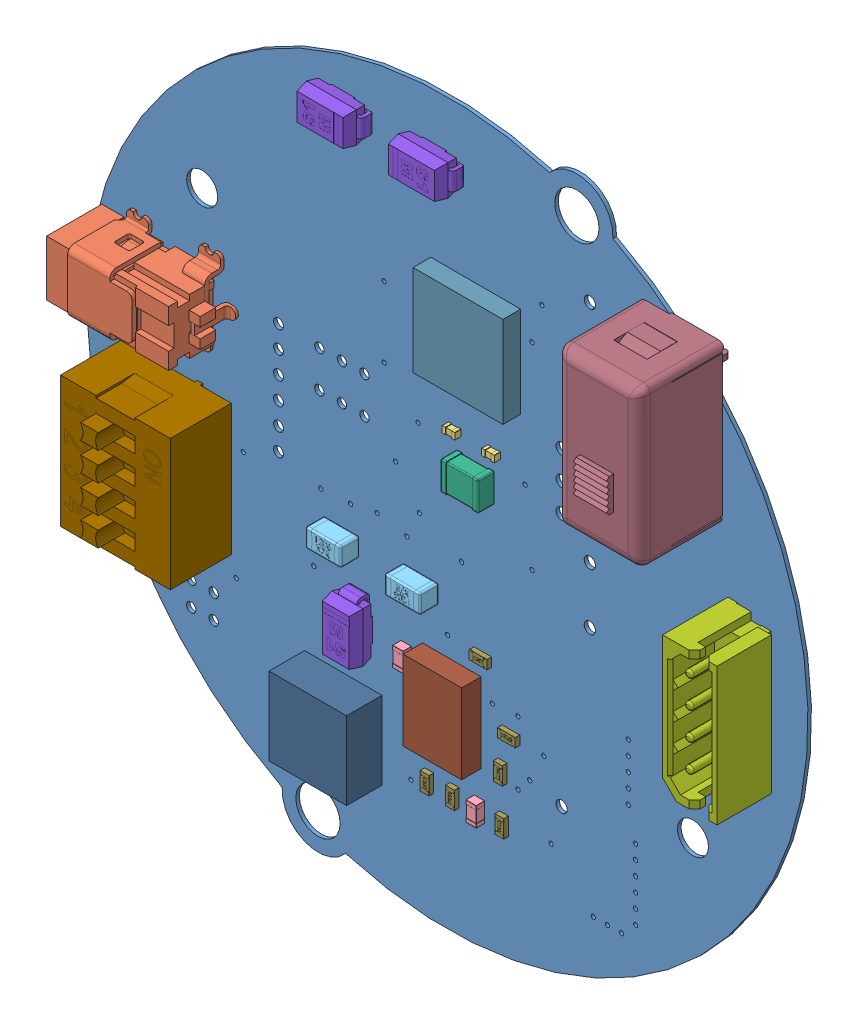
SolidWorks assembly sb, configuration Default. Lengths in mm.
Overall size (65 65 12.24).
40 component instances, 19 part files, 0 mates.
Components (placement in the parent):
- sb-1: sb [Default] at origin size (65 65 0.32)
- DRILL_4MM_DRILL_4MM-1: DRILL_4MM_DRILL_4MM [Default] at (11.6586 29.0576 0.3226) size (4.08 4.08 0)
- DRILL_4MM_DRILL_4MM-2: DRILL_4MM_DRILL_4MM [Default] at (-11.684 -29.083 0.3226) size (4.08 4.08 0)
- pj-032h-smt-tr-1: pj-032h-smt-tr [Default] at (-31.1624 6.0354 0.3105) x (0 -1 0) z (-1 0 0) size (8.2 6 12.3)
- 0402c_2320560-1: 0402c_2320560 [Default] at (0.635 6.858 0.3226) size (1.15 0.6 0.55)
- 0402c_2320560-2: 0402c_2320560 [Default] at (4.191 6.858 0.3226) x (-1 0 0) z (0 0 1) size (1.15 0.6 0.55)
- 0603C-1: 0603C [Default] at (2.794 -21.717 0.3226) x (0 -1 0) z (0 0 1) size (1.75 0.95 0.87)
- 0603C-2: 0603C [Default] at (-3.81 -12.954 0.3226) x (0 -1 0) z (0 0 1) size (1.75 0.95 0.87)
- Capacitor Vishay 1206 X7R-1: Capacitor Vishay 1206 X7R [По умолчанию] at (-9.525 -6.604 0.3226) size (3.2 1.7 1.7)
- Capacitor Vishay 1206 X7R-2: Capacitor Vishay 1206 X7R [По умолчанию] at (-2.3876 -6.7056 0.3226) x (-1 0 0) z (0 0 1) size (3.2 1.7 1.7)
- CAP1210-1: CAP1210 [Default] at (0.8315 4.0884 0.2929) x (1 0 0) z (0 -1 0) size (3.4 1.5 2.6)
- PORT-1: PORT [Default] at (27.7057 -0.1304 3.2566) x (0 1 0) z (1 0 0) size (12.4 9.4 4.9)
- DO-214AC-1: DO-214AC [Default] at (-9.398 27.051 1.3859) x (-1 0 0) z (0 0 1) size (5.28 2.79 2.29)
- DO-214AC-2: DO-214AC [Default] at (-1.143 27.051 1.3859) size (5.28 2.79 2.29)
- DO-214AC-3: DO-214AC [Default] at (-7.874 -12.3846 1.4768) x (0 -1 0) z (0 0 1) size (5.28 2.79 2.29)
- DS-4-1: DS-4 [Default] at (-29.1408 -0.9205 0.5763) x (0 -1 0) z (-1 0 0) size (11.82 10.4 9.9)
- HEADER_HEADER-1: HEADER_HEADER [Default] at (-21.082 -18.923 0.3226) size (2.12 2.13 0)
- HEADER_HEADER-2: HEADER_HEADER [Default] at (-21.082 -16.764 0.3226) size (2.12 2.13 0)
- HEADER_HEADER-3: HEADER_HEADER [Default] at (-23.114 -16.764 0.3226) size (2.12 2.13 0)
- HEADER_HEADER-4: HEADER_HEADER [Default] at (-23.114 -18.923 0.3226) size (2.12 2.13 0)
- HEADER_HEADER-5: HEADER_HEADER [Default] at (-11.557 3.81 0.3226) size (2.12 2.13 0)
- HEADER_HEADER-6: HEADER_HEADER [Default] at (-9.525 3.81 0.3226) size (2.12 2.13 0)
- HEADER_HEADER-7: HEADER_HEADER [Default] at (-7.493 3.81 0.3226) size (2.12 2.13 0)
- HEADER_HEADER-8: HEADER_HEADER [Default] at (-11.557 7.112 0.3226) size (2.12 2.13 0)
- HEADER_HEADER-9: HEADER_HEADER [Default] at (-9.525 7.112 0.3226) size (2.12 2.13 0)
- HEADER_HEADER-10: HEADER_HEADER [Default] at (-7.493 7.112 0.3226) size (2.12 2.13 0)
- inductor7mm-1: inductor7mm [Default] at (-5.907 -17.187 0.3226) x (-1 0 0) z (0 0 1) size (6.99 7.01 3.2)
- SOIC8_MP1584_BUCK_MP1584_BUCK-1: SOIC8_MP1584_BUCK_MP1584_BUCK [Default] at (0.381 -14.859 0.3226) x (0 1 0) z (0 0 1) size (7.18 5.28 1.75)
- ENCODER_MTR_ENCDR-1: ENCODER_MTR_ENCDR [Default] at (-15.24 2.159 0.3226) x (0 -1 0) z (0 0 1) size (12.22 2.31 0)
- RPI_BUCK_V2_PIZEROV1_3-1: RPI_BUCK_V2_PIZEROV1_3 [Default] at (11.557 0 0.3226) size (5.11 43.18 0)
- 0603_RES-1: 0603_RES [Default] at (0.635 -21.717 0.3226) x (0 1 0) z (0 0 1) size (1.6 0.8 0.46)
- 0603_RES-2: 0603_RES [Default] at (5.715 -14.478 0.3226) size (1.6 0.8 0.46)
- 0603_RES-3: 0603_RES [Default] at (4.953 -17.653 0.3226) x (0 -1 0) z (0 0 1) size (1.6 0.8 0.46)
- 0603_RES-4: 0603_RES [Default] at (-1.651 -21.717 0.3226) x (0 -1 0) z (0 0 1) size (1.6 0.8 0.46)
- 0603_RES-5: 0603_RES [Default] at (3.175 -9.652 0.3226) x (-1 0 0) z (0 0 1) size (1.6 0.8 0.46)
- 0603_RES-6: 0603_RES [Default] at (5.08 -21.717 0.3226) x (0 1 0) z (0 0 1) size (1.6 0.8 0.46)
- 25136nab-1: 25136nab [Default] at (21.0312 18.5166 0.3226) x (0 1 0) z (0 0 1) size (14.12 7.51 12.24)
- SSOP24_TB6612FNG_MTR_DRVR_TB6612FNG_MD-1: SSOP24_TB6612FNG_MTR_DRVR_TB6612FNG_MD [Default] at (2.54 15.113 0.3226) x (-1 0 0) z (0 0 1) size (8.1 8.2 1.6)
- DRILL_2_8MM_DRILL_2_8MM-1: DRILL_2_8MM_DRILL_2_8MM [Default] at (22.1234 -14.3002 0.3226) size (2.8 2.8 0)
- DRILL_2_8MM_DRILL_2_8MM-2: DRILL_2_8MM_DRILL_2_8MM [Default] at (-22.1234 14.3002 0.3226) size (2.8 2.8 0)
